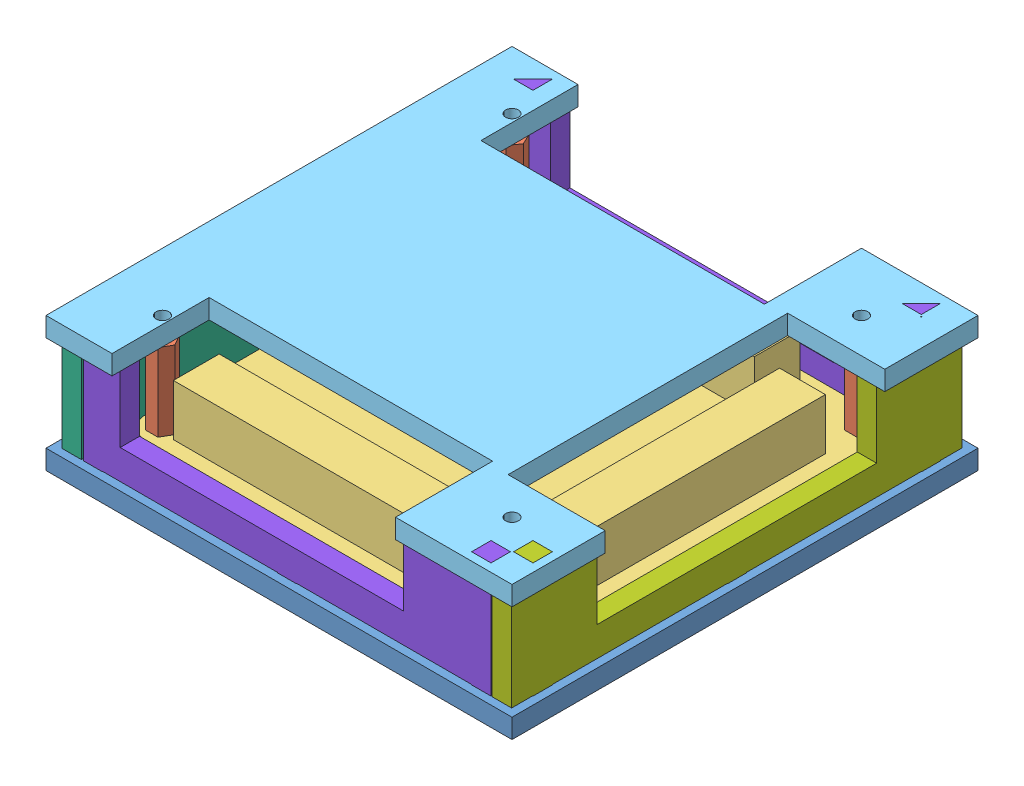
SolidWorks assembly case_assembled, configuration Default. Lengths in mm.
Overall size (120 34.6 120).
15 component instances, 8 part files, 33 mates.
Components (placement in the parent):
- base_plate-1: base_plate [Default] at (35.7404 44.7662 107.32) size (120 5 120)
- hex_pillar-1: hex_pillar [Default] at (-9.2596 54.3662 62.32) x (0.431834 0 0.901953) z (-0.901953 0 0.431834) size (6.35 20 5.5)
- pcb-1: pcb [Default] at (35.7404 52.7662 107.32) size (100 15.1 100)
- spacer-1: spacer [Default] at (-9.2596 49.7662 62.32) size (5 3 5)
- top_plate-1: top_plate [Default] at (35.7404 74.3662 107.32) size (120 5 120)
- spacer-2: spacer [Default] at (80.7404 49.7662 62.32) size (5 3 5)
- spacer-3: spacer [Default] at (-9.2596 49.7662 152.32) size (5 3 5)
- spacer-4: spacer [Default] at (80.7404 49.7662 152.32) size (5 3 5)
- hex_pillar-2: hex_pillar [Default] at (-9.2596 54.3662 152.32) size (6.35 20 5.5)
- hex_pillar-3: hex_pillar [Default] at (80.7404 54.3662 152.32) size (6.35 20 5.5)
- hex_pillar-4: hex_pillar [Default] at (80.7404 54.3662 62.32) size (6.35 20 5.5)
- side_ethernet-1: side_ethernet [Default] at (-17.1596 55.9162 107.32) x (0 0 1) z (-1 0 0) size (116 34.6 5)
- side_11-20-1: side_11-20 [Default] at (88.6404 55.9162 107.32) x (0 0 -1) z (1 0 0) size (116 34.6 5)
- side_1-10_and_21-30-1: side_1-10_and_21-30 [Default] at (35.7404 55.9162 54.42) x (-1 0 0) z (0 0 -1) size (105 34.6 5)
- side_1-10_and_21-30-2: side_1-10_and_21-30 [Default] at (35.7404 55.9162 165.22) x (-1 0 0) z (0 0 -1) size (105 34.6 5)
Mates (geometry in assembly coordinates):
- Concentric1: concentric anti-aligned: cylinder of base_plate-1 through (-9.2596 49.7662 62.32) axis (0 1 0) radius 1.65; cylinder of spacer-1 through (-9.2596 52.7662 62.32) axis (0 -1 0) radius 1.6
- Coincident1: coincident anti-aligned: plane of base_plate-1 through (35.7404 49.7662 107.32) normal (0 1 0); plane of spacer-1 through (-9.2596 49.7662 62.32) normal (0 -1 0)
- Coincident2: coincident anti-aligned: plane of base_plate-1 through (35.7404 49.7662 107.32) normal (0 1 0); plane of spacer-2 through (80.7404 49.7662 62.32) normal (0 -1 0)
- Concentric2: concentric anti-aligned: circle of base_plate-1; cylinder of spacer-2 through (80.7404 52.7662 62.32) axis (0 -1 0) radius 1.6
- Coincident3: coincident anti-aligned: plane of base_plate-1 through (35.7404 49.7662 107.32) normal (0 1 0); plane of spacer-3 through (-9.2596 49.7662 152.32) normal (0 -1 0)
- Concentric3: concentric anti-aligned: cylinder of base_plate-1 through (-9.2596 49.7662 152.32) axis (0 1 0) radius 1.65; cylinder of spacer-3 through (-9.2596 52.7662 152.32) axis (0 -1 0) radius 1.6
- Coincident4: coincident anti-aligned: plane of base_plate-1 through (35.7404 49.7662 107.32) normal (0 1 0); plane of spacer-4 through (80.7404 49.7662 152.32) normal (0 -1 0)
- Concentric4: concentric anti-aligned: cylinder of base_plate-1 through (80.7404 49.7662 152.32) axis (0 1 0) radius 1.65; cylinder of spacer-4 through (80.7404 52.7662 152.32) axis (0 -1 0) radius 1.6
- Concentric5: concentric anti-aligned: cylinder of pcb-1 through (-9.2596 54.3662 62.32) axis (0 1 0) radius 1.65; cylinder of spacer-1 through (-9.2596 52.7662 62.32) axis (0 -1 0) radius 1.6
- Concentric6: concentric anti-aligned: cylinder of pcb-1 through (-9.2596 54.3662 152.32) axis (0 1 0) radius 1.65; cylinder of spacer-3 through (-9.2596 52.7662 152.32) axis (0 -1 0) radius 1.6
- Coincident5: coincident anti-aligned: plane of pcb-1 through (35.7404 52.7662 107.32) normal (0 -1 0); plane of spacer-3 through (-9.2596 52.7662 152.32) normal (0 1 0)
- Concentric7: concentric aligned: circle of hex_pillar-1; cylinder of pcb-1 through (-9.2596 54.3662 62.32) axis (0 1 0) radius 1.65
- Coincident6: coincident anti-aligned: plane of hex_pillar-1 through (-9.2596 54.3662 62.32) normal (0 -1 0); plane of pcb-1 through (35.7404 54.3662 107.32) normal (0 1 0)
- Coincident7: coincident anti-aligned: circle of pcb-1; plane of hex_pillar-2 through (-9.2596 54.3662 152.32) normal (0 -1 0)
- Concentric8: concentric aligned: circle of pcb-1; circle of hex_pillar-2
- Coincident8: coincident anti-aligned: plane of pcb-1 through (35.7404 54.3662 107.32) normal (0 1 0); plane of hex_pillar-3 through (80.7404 54.3662 152.32) normal (0 -1 0)
- Concentric9: concentric anti-aligned: circle of pcb-1; cylinder of hex_pillar-3 through (80.7404 74.3662 152.32) axis (0 -1 0) radius 1.5
- Coincident9: coincident anti-aligned: plane of pcb-1 through (35.7404 54.3662 107.32) normal (0 1 0); plane of hex_pillar-4 through (80.7404 54.3662 62.32) normal (0 -1 0)
- Concentric10: concentric anti-aligned: circle of pcb-1; cylinder of hex_pillar-4 through (80.7404 74.3662 62.32) axis (0 -1 0) radius 1.5
- Concentric11: concentric anti-aligned: circle of top_plate-1; cylinder of hex_pillar-2 through (-9.2596 74.3662 152.32) axis (0 -1 0) radius 1.5
- Concentric12: concentric anti-aligned: cylinder of hex_pillar-1 through (-9.2596 74.3662 62.32) axis (0 -1 0) radius 1.5; cylinder of top_plate-1 through (-9.2596 79.3662 62.32) axis (0 1 0) radius 1.65
- Coincident10: coincident anti-aligned: plane of base_plate-1 through (-17.1596 44.7662 104.82) normal (-1 0 0); plane of side_ethernet-1 through (-17.1596 55.9162 107.32) normal (1 0 0)
- Coincident11: coincident anti-aligned: plane of base_plate-1 through (-22.2596 44.7662 104.82) normal (0 0 1); plane of side_ethernet-1 through (-22.1596 44.7662 104.82) normal (0 0 -1)
- Coincident12: coincident anti-aligned: plane of base_plate-1 through (35.7404 49.7662 107.32) normal (0 1 0); plane of side_ethernet-1 through (-22.1596 49.7662 49.32) normal (0 -1 0)
- Coincident15: coincident anti-aligned: plane of base_plate-1 through (88.6404 44.7662 104.82) normal (0 0 1); plane of side_11-20-1 through (93.6404 44.7662 104.82) normal (0 0 -1)
- Coincident16: coincident anti-aligned: plane of base_plate-1 through (88.6404 44.7662 104.82) normal (1 0 0); plane of side_11-20-1 through (88.6404 55.9162 107.32) normal (-1 0 0)
- Coincident17: coincident anti-aligned: plane of base_plate-1 through (35.7404 49.7662 107.32) normal (0 1 0); plane of side_11-20-1 through (93.6404 49.7662 165.32) normal (0 -1 0)
- Coincident18: coincident anti-aligned: plane of base_plate-1 through (33.2404 44.7662 54.42) normal (0 0 -1); plane of side_1-10_and_21-30-1 through (35.7404 55.9162 54.42) normal (0 0 1)
- Coincident19: coincident anti-aligned: plane of base_plate-1 through (35.7404 49.7662 107.32) normal (0 1 0); plane of side_1-10_and_21-30-1 through (88.2404 49.7662 49.42) normal (0 -1 0)
- Coincident20: coincident anti-aligned: plane of base_plate-1 through (88.2404 44.7662 49.32) normal (-1 0 0); plane of side_1-10_and_21-30-1 through (88.2404 49.7662 49.42) normal (1 0 0)
- Coincident21: coincident anti-aligned: plane of base_plate-1 through (33.2404 44.7662 160.22) normal (0 0 1); plane of side_1-10_and_21-30-2 through (35.7404 55.9162 160.22) normal (0 0 -1)
- Coincident22: coincident anti-aligned: plane of base_plate-1 through (35.7404 49.7662 107.32) normal (0 1 0); plane of side_1-10_and_21-30-2 through (88.2404 49.7662 160.22) normal (0 -1 0)
- Coincident23: coincident anti-aligned: plane of base_plate-1 through (88.2404 44.7662 160.22) normal (-1 0 0); plane of side_1-10_and_21-30-2 through (88.2404 49.7662 160.22) normal (1 0 0)
